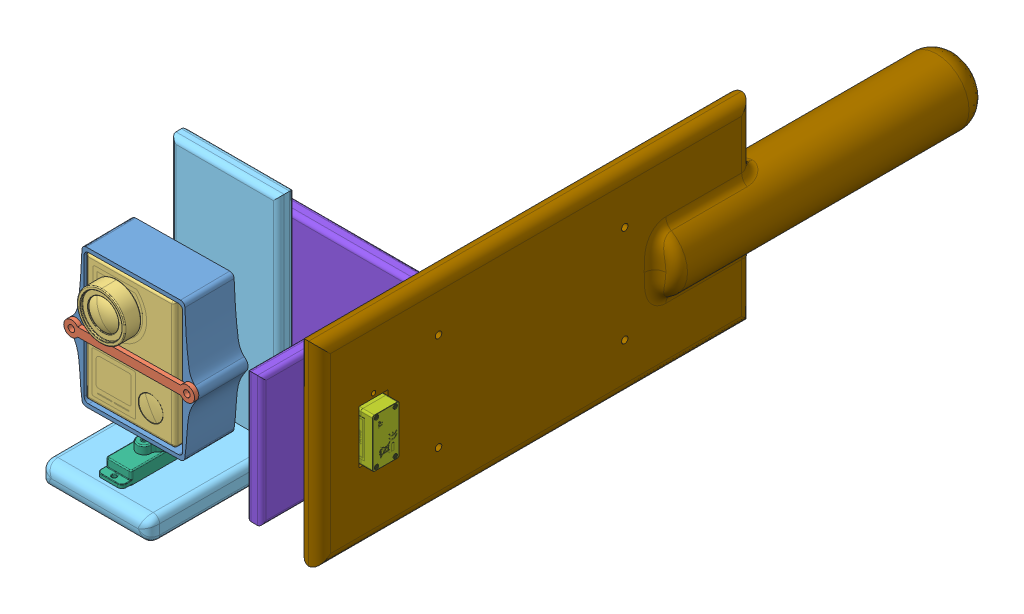
SolidWorks assembly Ensamblaje, configuration Predeterminado. Lengths in mm.
Overall size (135.24 116.15 308.67).
10 component instances, 9 part files, 26 mates.
Components (placement in the parent):
- Pieza 1-2: Pieza 1 [Predeterminado] at (-6.6089 0.3899 -10.3727) x (-0.011482 0 -0.999934) z (0.999934 0 -0.011482) size (30 66 59.74)
- Freno-1: Freno [Predeterminado] at (-6.3449 -1.6101 12.6258) x (-0.999934 0 0.011482) z (-0.011482 0 -0.999934) size (59.74 7 2)
- Gopro Hero 4-1: Gopro Hero 4 [Predeterminado] at (-8.6588 0.3899 -10.3492) x (0.011482 0 0.999934) z (-0.999934 0 0.011482) size (28.53 59.01 41.48)
- GY-91-1: GY-91 [Predeterminado] at (-0.7595 -10.1301 -14.4401) x (-0.999933 0.001681 0.011482) z (-0.011482 0 -0.999934) size (14.4 21 3.02)
- Pieza2-1: Pieza2 [Predeterminado] at (-6.4941 -50.8601 -1.6234) x (0 1 0) z (-1 0 0) size (110.02 67.53 50.05)
- Emax ES08A-1: Emax ES08A [Default] at (-6.4941 -61.2601 5.6266) x (0 0 -1) z (1 0 0) size (32 27.65 11.68)
- SG90 - Micro Servo 9g - Tower Pro.1-1: SG90 - Micro Servo 9g - Tower Pro.1 [Peça] at (-6.4941 4.2899 -53.4234) x (0 1 0) z (1 0 0) size (32.1 29.95 12.4)
- Pieza3-1: Pieza3 [Predeterminado] at (18.5059 4.3899 -51.7734) x (0 1 0) z (1 0 0) size (60 80 93.5)
- SG90 - Micro Servo 9g - Tower Pro.1-2: SG90 - Micro Servo 9g - Tower Pro.1 [Peça] at (83.8059 9.5399 -5.2734) x (0 1 0) z (0 0 1) size (32.1 29.95 12.4)
- Pieza4-1: Pieza4 [Predeterminado] at (88.6559 9.8899 -80.2734) x (0 0 -1) z (0 1 0) size (300 30 90)
Mates (geometry in assembly coordinates):
- Coincidente1: coincident: plane of assembly; plane of assembly; plane of Pieza 1-2 through (-6.3678 0.3899 10.6259) normal (0.011482 0 0.999934); plane of Freno-1 through (-6.3678 -1.6101 10.6259) normal (-0.011482 0 -0.999934)
- Concéntrica1: concentric: circle of assembly; circle of assembly; circle of Pieza 1-2; circle of Freno-1
- Concéntrica6: concentric: circle of assembly; circle of assembly; circle of Pieza 1-2; circle of Freno-1
- Concéntrica7: concentric: cylinder of assembly; cylinder of assembly; cylinder of Pieza 1-2 through (-36.3654 -17.9101 -0.0304) axis (0.999934 0 -0.011482) radius 6; cylinder of Gopro Hero 4-1 through (-26.9928 -17.9101 -0.138) axis (-0.999934 0 0.011482) radius 5.575
- Coincidente3: coincident: plane of assembly; plane of assembly; plane of Pieza 1-2 through (-6.6089 0.3899 -10.3727) normal (0.011482 0 0.999934); plane of Gopro Hero 4-1 through (-8.6588 0.3899 -10.3492) normal (-0.011482 0 -0.999934)
- Paralelo2: parallel: plane of assembly; plane of assembly; plane of Pieza 1-2 through (-6.6089 0.3899 -10.3727) normal (0.011482 0 0.999934); plane of Gopro Hero 4-1 through (-8.6588 0.3899 -10.3492) normal (-0.011482 0 -0.999934)
- Coincidente5: coincident: plane of assembly; plane of assembly; plane of Pieza 1-2 through (-28.8663 -29.8601 10.8843) normal (0.999934 0 -0.011482); plane of Gopro Hero 4-1 through (-29.1075 -29.1101 -10.1144) normal (-0.999934 0 0.011482)
- Concéntrica8: concentric: cylinder of assembly; cylinder of assembly; cylinder of GY-91-1 through (-12.6545 -7.6101 -14.3035) axis (-0.011482 0 -0.999934) radius 1.6; cylinder of Pieza 1-2 through (-12.6545 -7.6101 -14.3035) axis (0.011482 0 0.999934) radius 1.5
- Coincidente6: coincident: plane of assembly; plane of assembly; plane of Pieza 1-2 through (-6.6549 0.3899 -14.3724) normal (-0.011482 0 -0.999934); plane of GY-91-1 through (-7.9413 0.382 -14.3577) normal (0.011482 0 0.999934)
- Concéntrica9: concentric: circle of assembly; circle of assembly; circle of Pieza 1-2; circle of Emax ES08A-1
- Paralelo4: parallel: plane of assembly; plane of assembly; plane of Pieza2-1 through (-12.6191 -55.8611 17.8766) normal (1 0 0); plane of Emax ES08A-1 through (-12.2941 -40.4601 17.4266) normal (-1 0 0)
- Concéntrica12: concentric: circle of assembly; circle of assembly; circle of Pieza2-1; circle of Emax ES08A-1
- Coincidente11: coincident: plane of assembly; plane of assembly; plane of Pieza2-1 through (-6.4941 -45.8601 -1.6234) normal (0 1 0); plane of Emax ES08A-1 through (-12.2941 -45.8601 -10.3734) normal (0 -1 0)
- Coincidente12: coincident: plane of assembly; plane of assembly; plane of Pieza2-1 through (-6.4941 -0.8601 -34.1234) normal (0 0 -1); plane of SG90 - Micro Servo 9g - Tower Pro.1-1 through (-6.4941 -0.8601 -34.1234) normal (0 0 1)
- Paralelo5: parallel: plane of assembly; plane of assembly; plane of Pieza2-1 through (-31.4941 -55.8601 28.3766) normal (-1 0 0); plane of SG90 - Micro Servo 9g - Tower Pro.1-1 through (-0.3941 14.6899 -63.9734) normal (1 0 0)
- Coincidente13: coincident: plane of assembly; plane of assembly; plane of Pieza 1-2 through (-6.4941 -33.6101 -0.3734) normal (0 -1 0); plane of Emax ES08A-1 through (-6.4941 -33.6101 5.2681) normal (0 1 0)
- Concéntrica13: concentric: circle of assembly; circle of assembly; circle of Pieza2-1; circle of SG90 - Micro Servo 9g - Tower Pro.1-1
- Concéntrica14: concentric: circle of assembly; circle of assembly; circle of SG90 - Micro Servo 9g - Tower Pro.1-1; circle of Pieza3-1
- Paralelo7: parallel: plane of assembly; plane of assembly; plane of SG90 - Micro Servo 9g - Tower Pro.1-1 through (-1.2441 15.5399 -48.2734) normal (0 1 0); plane of Pieza3-1 through (0.7559 16.6399 -55.2744) normal (0 -1 0)
- Coincidente18: coincident: plane of assembly; plane of assembly; plane of SG90 - Micro Servo 9g - Tower Pro.1-1 through (-1.2441 -10.9101 -48.2734) normal (0 0 -1); plane of Pieza3-1 through (18.5059 4.3899 -48.2734) normal (0 0 1)
- Coincidente19: coincident: plane of assembly; plane of assembly; plane of Pieza3-1 through (64.5059 4.3899 -5.2734) normal (1 0 0); plane of SG90 - Micro Servo 9g - Tower Pro.1-2 through (64.5059 4.3899 -5.2734) normal (-1 0 0)
- Concéntrica17: concentric: circle of assembly; circle of assembly; circle of Pieza3-1; circle of SG90 - Micro Servo 9g - Tower Pro.1-2
- Concéntrica18: concentric: circle of assembly; circle of assembly; circle of SG90 - Micro Servo 9g - Tower Pro.1-2; circle of Pieza4-1
- Paralelo8: parallel: plane of assembly; plane of assembly; plane of Pieza3-1 through (63.5059 34.3899 -55.2734) normal (0 1 0); plane of SG90 - Micro Servo 9g - Tower Pro.1-2 through (76.1559 25.5899 -0.0234) normal (0 1 0)
- Paralelo9: parallel: plane of assembly; plane of assembly; plane of SG90 - Micro Servo 9g - Tower Pro.1-2 through (78.6559 20.7899 -0.0234) normal (0 1 0); plane of Pieza4-1 through (78.6559 22.1399 1.4766) normal (0 -1 0)
- Coincidente22: coincident: plane of assembly; plane of assembly; plane of SG90 - Micro Servo 9g - Tower Pro.1-2 through (78.6559 -5.6601 -0.0234) normal (1 0 0); plane of Pieza4-1 through (78.6559 9.8899 -80.2734) normal (-1 0 0)
